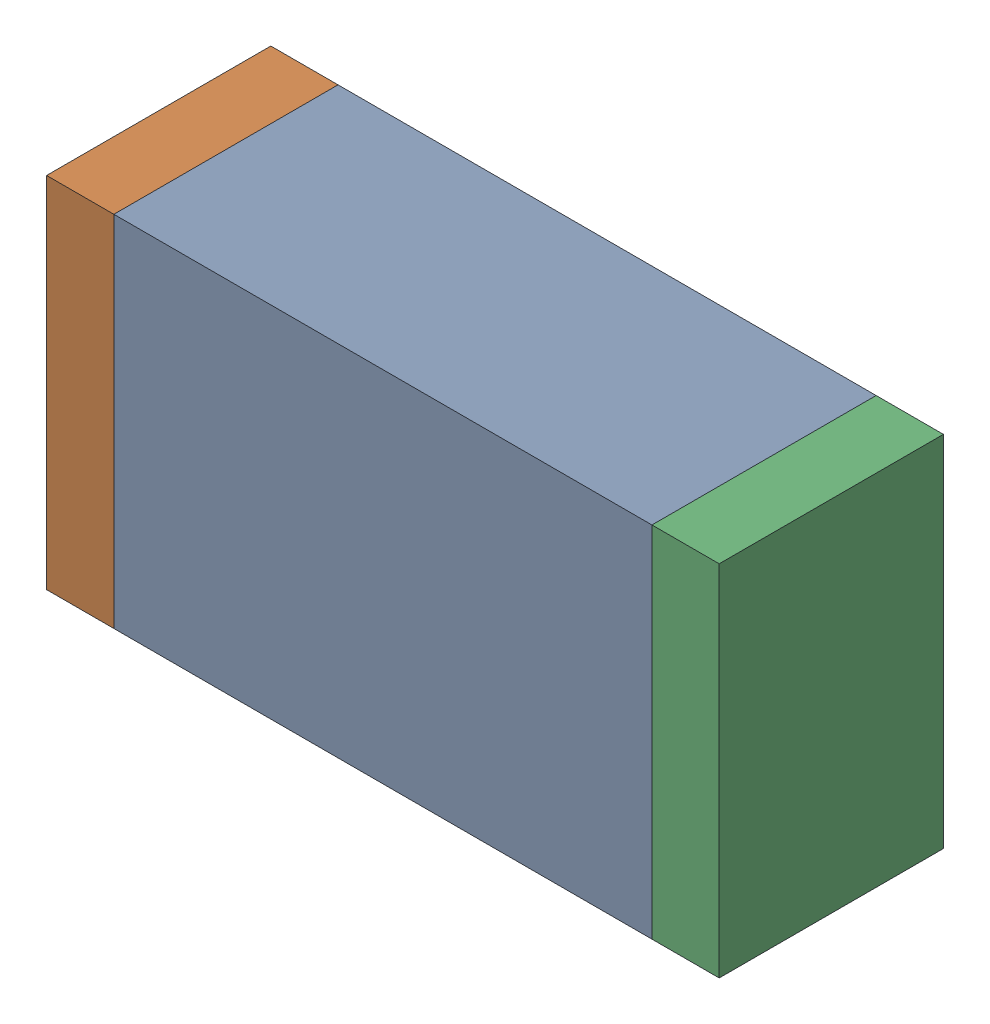
SolidWorks assembly R3, configuration Default. Lengths in mm.
Overall size (1.5 0.8 0.5).
6 component instances, 2 part files, 0 mates.
Components (placement in the parent):
- 836752368-1: 836752368 [Default] at (128.3 29.4 0) size (1.2 0.8 0.5)
  - Extruded-1: Extruded [Default] at origin size (1.2 0.8 0.5)
- 836752496-1: 836752496 [Default] at (127.625 29.4 0) size (0.15 0.8 0.5)
  - Extruded_2-1: Extruded_2 [Default] at origin size (0.15 0.8 0.5)
- 836752496-2: 836752496 [Default] at (128.975 29.4 0) size (0.15 0.8 0.5)
  - Extruded_2-1: Extruded_2 [Default] at origin size (0.15 0.8 0.5)
